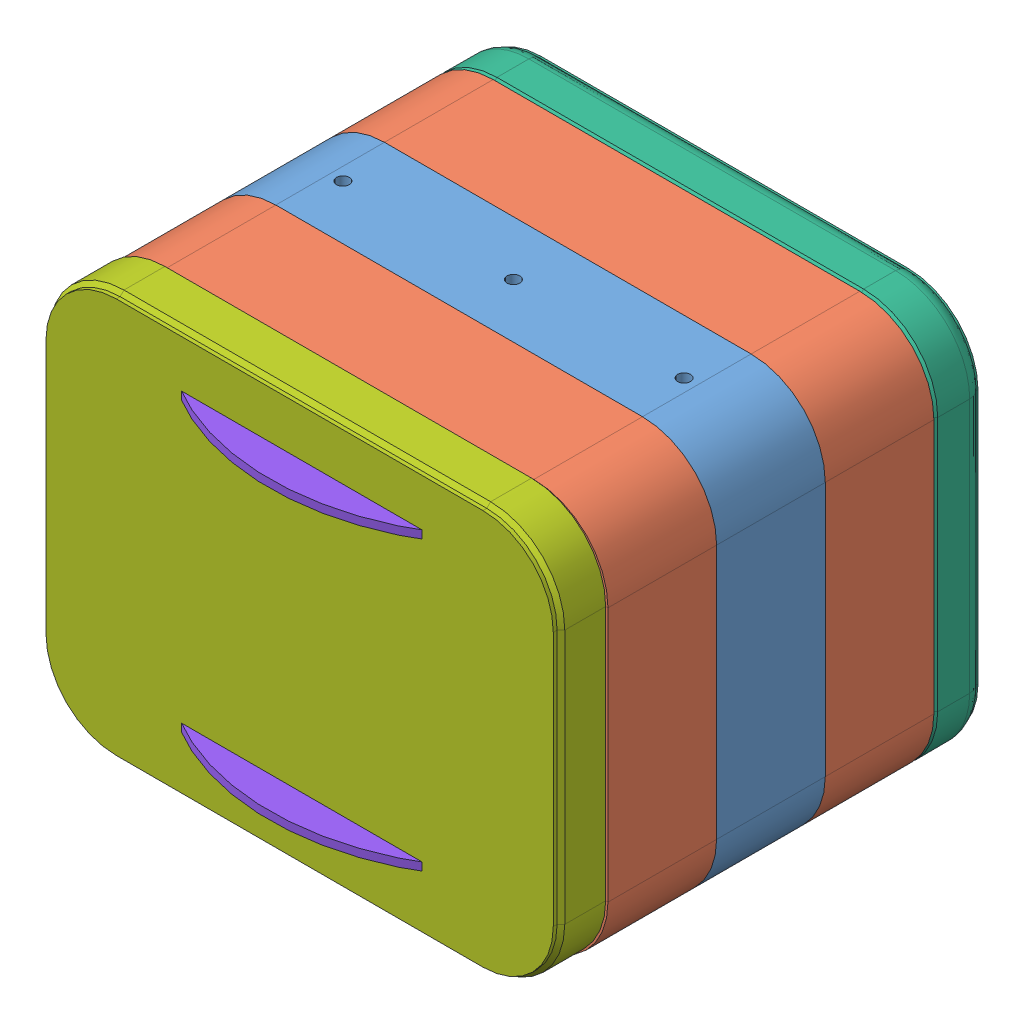
SolidWorks assembly DehydratorV2Assem, configuration Default. Lengths in mm.
Overall size (323.74 282.46 296.43).
19 component instances, 11 part files, 31 mates.
Components (placement in the parent):
- TrayMiddle-1: TrayMiddle [Default] at origin size (322.3 252.3 70.4)
- TraySpacer-1: TraySpacer [Default] at (0 0 -68) size (322.3 252.3 70.4)
- TraySpacer-2: TraySpacer [Default] at (0 0 68) size (322.3 252.3 70.4)
- TempHumidityMeter-1: TempHumidityMeter [Default] at (158.75 11.3 -36.4) x (-0.999802 0 0.01989) z (0 -1 0) size (45.4 45.4 15.54)
- Bearing22x7x8-1: Bearing22x7x8 [Default] at (7 123.75 -35.2) x (0 0.983216 0.182446) z (-1 0 0) size (22 22 7)
- Bearing22x7x8-2: Bearing22x7x8 [Default] at (104 123.75 -35.2) x (0 -0.06844 -0.997655) z (-1 0 0) size (22 22 7)
- Bearing22x7x8-3: Bearing22x7x8 [Default] at (106.75 123.75 -35.2) x (0 -0.999713 -0.023971) z (1 0 0) size (22 22 7)
- Bearing22x7x8-4: Bearing22x7x8 [Default] at (210.75 123.75 -35.2) x (0 0 1) z (-1 0 0) size (22 22 7)
- Bearing22x7x8-5: Bearing22x7x8 [Default] at (213.5 123.75 -35.2) x (0 0 -1) z (1 0 0) size (22 22 7)
- Bearing22x7x8-6: Bearing22x7x8 [Default] at (317.5 123.75 -35.2) x (0 0.901938 0.431866) z (-1 0 0) size (22 22 7)
- FilamentSpool200x72mm-1: FilamentSpool200x72mm [Default] at (307.5 123.75 -15.6) x (0 -0.229729 0.973255) z (-1 0 0) size (200 200 73.24)
- FilamentSpool200x72mm-2: FilamentSpool200x72mm [Default] at (200.75 123.75 -15.6) x (0 -0.143363 0.98967) z (-1 0 0) size (200 200 73.24)
- FilamentSpool200x72mm-3: FilamentSpool200x72mm [Default] at (94 123.75 -15.6) x (0 -0.742698 0.669626) z (-1 0 0) size (200 200 73.24)
- TrayV2Lid-1: TrayV2Lid [Default] at (0 0 -136) size (322.3 252.3 34.8)
- TrayV2CaptiveBase-1: TrayV2CaptiveBase [Default] at (-1.4447 0 96) size (322.3 252.3 30.4)
- Spool5kg-1: Spool5kg [Default] at (158.75 32.9759 -36.4) x (0.915657 0 -0.40196) z (0 1 0) size (305 305 185) (hidden)
- ClearRoll53x85-1: ClearRoll53x85 [Default] at (308 123.75 -35.2) x (0 0 1) z (-1 0 0) size (53 53 94.5)
- ClearRoll32x85-1: ClearRoll32x85 [Default] at (201.25 123.75 -35.2) x (0 -0.09985 0.995003) z (-1 0 0) size (32 32 94.5)
- ClearRoll72x85-1: ClearRoll72x85 [Default] at (94.5 123.75 -35.2) x (0 -0.069859 0.997557) z (-1 0 0) size (72 72 94.5)
Mates (geometry in assembly coordinates):
- Coincident2: coincident anti-aligned: plane of TrayV2wSupport2-1 through (104 123.75 -35.2) normal (-1 0 0); plane of Bearing22x7x8-2 through (104 123.75 -35.2) normal (1 0 0)
- Coincident3: coincident anti-aligned: plane of TrayV2wSupport2-1 through (106.75 123.75 -35.2) normal (1 0 0); plane of Bearing22x7x8-3 through (106.75 123.75 -35.2) normal (-1 0 0)
- Coincident6: coincident anti-aligned: plane of TrayV2wSupport2-1 through (317.5 123.75 -35.2) normal (-1 0 0); plane of Bearing22x7x8-6 through (317.5 123.75 -35.2) normal (1 0 0)
- Concentric3: concentric anti-aligned: cylinder of TrayV2wSupport2-1 through (106.75 123.75 -35.2) axis (1 0 0) radius 11.125; cylinder of Bearing22x7x8-3 through (113.75 123.75 -35.2) axis (-1 0 0) radius 11
- Concentric4: concentric anti-aligned: cylinder of TrayV2wSupport2-1 through (104 123.75 -35.2) axis (-1 0 0) radius 11.125; cylinder of Bearing22x7x8-2 through (97 123.75 -35.2) axis (1 0 0) radius 11
- Coincident12: coincident anti-aligned: plane of TrayV2wSupport2-1 through (213.5 123.75 -35.2) normal (1 0 0); plane of Bearing22x7x8-5 through (213.5 123.75 -35.2) normal (-1 0 0)
- Concentric14: concentric anti-aligned: cylinder of TrayV2wSupport2-1 through (213.5 123.75 -35.2) axis (1 0 0) radius 11.125; cylinder of Bearing22x7x8-5 through (220.5 123.75 -35.2) axis (-1 0 0) radius 11
- Coincident13: coincident anti-aligned: plane of TrayV2wSupport2-1 through (210.75 123.75 -35.2) normal (-1 0 0); plane of Bearing22x7x8-4 through (210.75 123.75 -35.2) normal (1 0 0)
- Concentric15: concentric anti-aligned: cylinder of TrayV2wSupport2-1 through (210.75 123.75 -35.2) axis (-1 0 0) radius 11.125; cylinder of Bearing22x7x8-4 through (203.75 123.75 -35.2) axis (1 0 0) radius 11
- Concentric16: concentric anti-aligned: cylinder of TrayV2wSupport2-1 through (7 123.75 -35.2) axis (-1 0 0) radius 11.125; cylinder of Bearing22x7x8-1 through (0 123.75 -35.2) axis (1 0 0) radius 11
- Coincident20: coincident aligned: line of TrayV2wSupport2-1 through (317.5 203.5 -70.4) axis (0 -1 0); line of TrayV2Top-1 through (317.5 203.5 -70.4) axis (0 -1 0)
- Coincident21: coincident aligned: line of TrayV2Top-1 through (317.5 203.5 -138.4) axis (0 -1 0); line of TrayV2Lid-1 through (317.5 203.5 -138.4) axis (0 -1 0)
- Coincident22: coincident aligned: line of TrayV2Top-1 through (44 247.5 -138.4) axis (1 0 0); line of TrayV2Lid-1 through (44 247.5 -138.4) axis (1 0 0)
- Concentric18: concentric anti-aligned: cylinder of TrayV2wSupport2-1 through (158.75 232.1863 -36.4) axis (0 1 0) radius 4; cylinder of Spool5kg-1 through (158.75 217.9759 -36.4) axis (0 -1 0) radius 25.4
- Distance4: distance = 2.5 mm anti-aligned: plane of ClearRoll53x85-1 through (308 123.75 -35.2) normal (1 0 0); plane of Bearing22x7x8-6 through (310.5 123.75 -35.2) normal (-1 0 0)
- Concentric19: concentric aligned: cylinder of Bearing22x7x8-6 through (310.5 123.75 -35.2) axis (1 0 0) radius 4.075; cylinder of ClearRoll53x85-1 through (303 123.75 -35.2) axis (1 0 0) radius 4
- Distance5: distance = 2.5 mm anti-aligned: plane of ClearRoll32x85-1 through (201.25 123.75 -35.2) normal (1 0 0); plane of Bearing22x7x8-4 through (203.75 123.75 -35.2) normal (-1 0 0)
- Distance6: distance = 2.5 mm anti-aligned: plane of ClearRoll72x85-1 through (94.5 123.75 -35.2) normal (1 0 0); plane of Bearing22x7x8-2 through (97 123.75 -35.2) normal (-1 0 0)
- Concentric20: concentric aligned: cylinder of Bearing22x7x8-4 through (203.75 123.75 -35.2) axis (1 0 0) radius 4.075; cylinder of ClearRoll32x85-1 through (196.25 123.75 -35.2) axis (1 0 0) radius 4
- Concentric21: concentric aligned: cylinder of Bearing22x7x8-2 through (97 123.75 -35.2) axis (1 0 0) radius 4.075; cylinder of ClearRoll72x85-1 through (89.5 123.75 -35.2) axis (1 0 0) radius 4
- Concentric22: concentric anti-aligned: cylinder of TrayV2wSupport2-1 through (158.75 249.901 -36.4) axis (0 -1 0) radius 21.25; cylinder of TempHumidityMeter-1 through (158.75 -2.4 -36.4) axis (0 1 0) radius 21
- Coincident28: coincident anti-aligned: plane of TrayV2wSupport2-1 through (0 44 -5.8549) normal (1 0 0); plane of Bearing22x7x8-1 through (0 123.75 -35.2) normal (-1 0 0)
- Coincident29: coincident anti-aligned: plane of TrayV2wSupport2-1 through (317.5 123.75 -35.2) normal (-1 0 0); plane of Bearing22x7x8-6 through (317.5 123.75 -35.2) normal (1 0 0)
- Concentric23: concentric aligned: cylinder of TrayV2wSupport2-1 through (310.5 123.75 -35.2) axis (1 0 0) radius 11.125; cylinder of Bearing22x7x8-6 through (310.5 123.75 -35.2) axis (1 0 0) radius 11
- Coincident30: coincident aligned: plane of TrayV2wSupport2-1 through (44 249.9 -70.4) normal (0 1 0); plane of TrayV2Top-1 through (44 249.9 -138.4) normal (0 1 0)
- Coincident31: coincident anti-aligned: plane of TrayV2wSupport2-1 through (44 247.5 -70.4) normal (0 0 -1); plane of TrayV2Top-1 through (44 247.5 -70.4) normal (0 0 1)
- Coincident32: coincident anti-aligned: plane of TrayV2wSupport2-1 through (44 247.5 -2.4) normal (0 0 1); plane of TrayV2Top-2 through (44 247.5 -2.4) normal (0 0 -1)
- Coincident33: coincident aligned: plane of TrayV2wSupport2-1 through (44 249.9 -70.4) normal (0 1 0); plane of TrayV2Top-2 through (44 249.9 -2.4) normal (0 1 0)
- Coincident34: coincident aligned: plane of TrayV2wSupport2-1 through (-2.4 44 -70.4) normal (-1 0 0); plane of TrayV2Top-2 through (-2.4 44 -2.4) normal (-1 0 0)
- Coincident35: coincident anti-aligned: plane of TraySpacer-2 through (317.5 203.5 65.6) normal (0 0 1); plane of TrayV2CaptiveBase-1 through (316.0553 203.5 65.6) normal (0 0 -1)
- Coincident37: coincident aligned: plane of TraySpacer-2 through (44 249.9 -2.4) normal (0 1 0); plane of TrayV2CaptiveBase-1 through (42.5553 249.9 65.6) normal (0 1 0)
